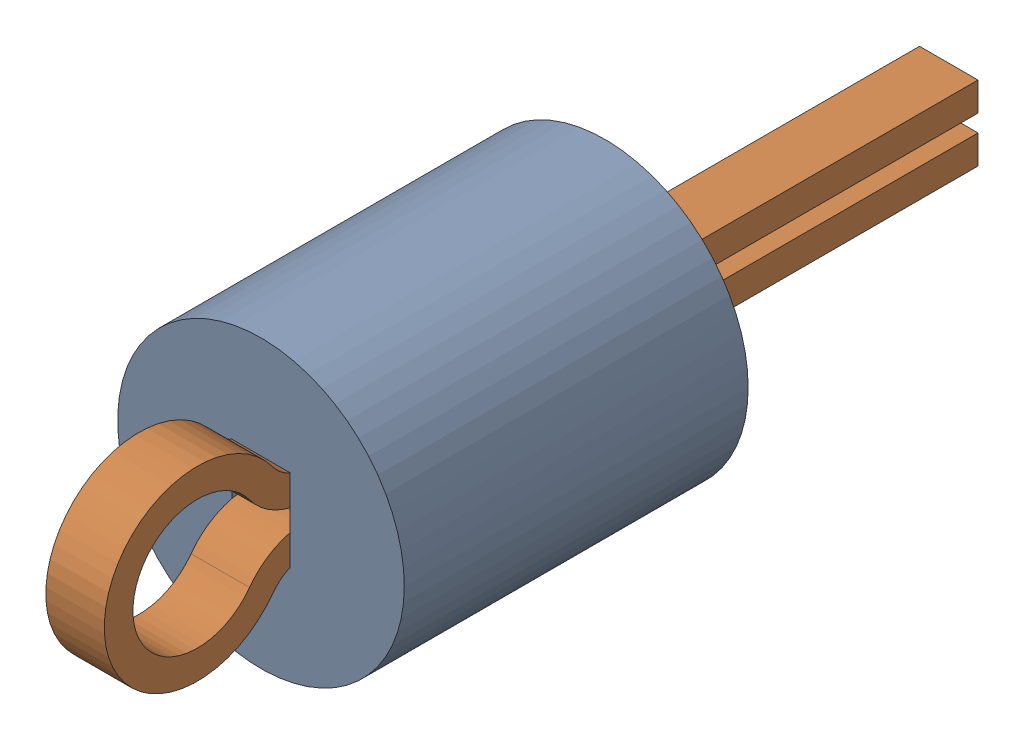
SolidWorks assembly TP7, configuration Default. Lengths in mm.
Overall size (2.5 2.5 7.62).
3 component instances, 2 part files, 0 mates.
Components (placement in the parent):
- Keystone_5002-1: Keystone_5002 [Default] at (43.1755 31.7529 0) size (2.5 2.5 7.62)
  - Keystone5002_white-1: Keystone5002_white [Default] at origin size (2.5 2.5 3)
  - Keystone500x_wire-1: Keystone500x_wire [Default] at origin size (0.51 1.62 7.62)
